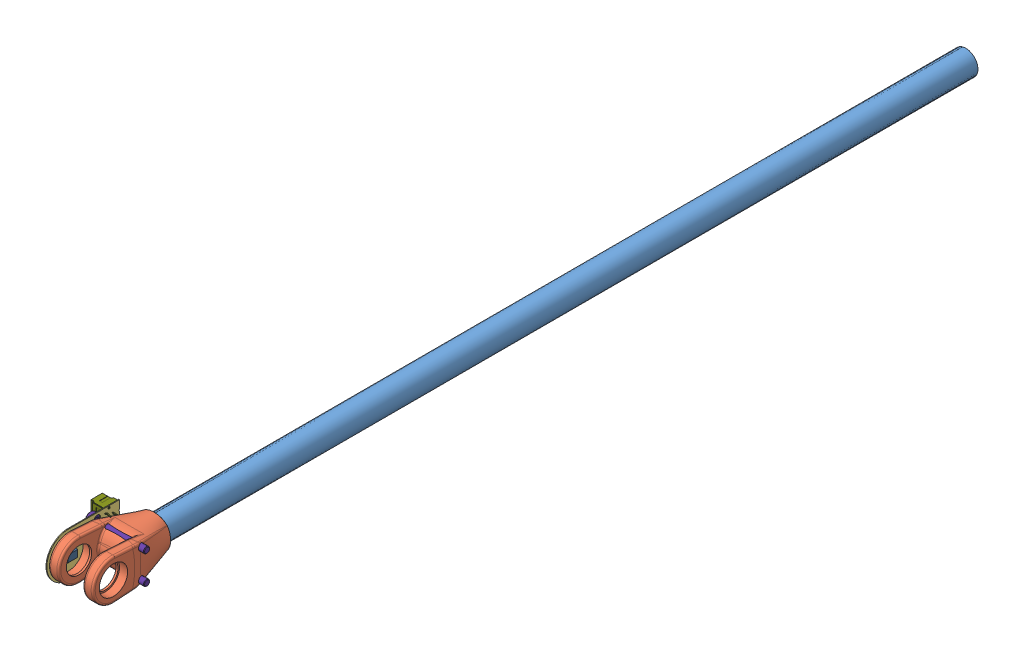
SolidWorks assembly Tilt_Joint, configuration Default. Lengths in mm.
Overall size (31.95 100.9 442.9).
34 component instances, 17 part files, 17 mates.
Components (placement in the parent):
- CF Tube-1: CF Tube [Full Length] x (1 0 0) z (0 -1 0) size (12 420 12)
- Tilt_Joint_Outside-1: Tilt_Joint_Outside [Default] at (0 0 432) x (-1 0 0) z (0 0 -1) size (22.1 20.15 42.34)
- Encoder_Board_REV_A-1: Encoder_Board_REV_A [Default] at (-11 -90 384) x (0 0 1) z (-1 0 0) size (58.9 100.9 10.35)
  - Encoder_Board_REV_A_BOARD-1: Encoder_Board_REV_A_BOARD [Default] at origin size (58.9 100.9 0.41)
  - RESC0603(1608)_N_CMP-009-00178-1-1: RESC0603(1608)_N_CMP-009-00178-1 [Default] at (38.479 98.166 0.4013) size (1.7 0.95 0.6)
  - WL-SMCW_0603_150060xx75000_CMP-007-00036-1-1: WL-SMCW_0603_150060xx75000_CMP-007-00036-1 [Default] at (41.273 97.366 0.4013) x (0 -1 0) z (0 0 1) size (1.6 0.8 0.7)
  - RESC1608X55X25NL10T15_CMP-009-00017-7-1: RESC1608X55X25NL10T15_CMP-009-00017-7 [Default] at (43.17 92.667 0.4013) x (0 1 0) z (0 0 1) size (1.7 0.9 0.55)
  - RESC1608X55X25NL10T15_CMP-009-00017-7-2: RESC1608X55X25NL10T15_CMP-009-00017-7 [Default] at (43.17 90 0.4013) x (0 -1 0) z (0 0 1) size (1.7 0.9 0.55)
  - RESC1608X55X25NL10T15_CMP-009-00017-7-3: RESC1608X55X25NL10T15_CMP-009-00017-7 [Default] at (34.669 90 0.4013) x (0 -1 0) z (0 0 1) size (1.7 0.9 0.55)
  - RESC1608X55X25NL10T15_CMP-009-00017-7-4: RESC1608X55X25NL10T15_CMP-009-00017-7 [Default] at (34.669 92.667 0.4013) x (0 1 0) z (0 0 1) size (1.7 0.9 0.55)
  - RESC1608X55X25NL10T15_CMP-009-00017-7-5: RESC1608X55X25NL10T15_CMP-009-00017-7 [Default] at (41.273 88.349 0.4013) x (0 -1 0) z (0 0 1) size (1.7 0.9 0.55)
  - RESC1608X55X25NL10T15_CMP-009-00017-7-6: RESC1608X55X25NL10T15_CMP-009-00017-7 [Default] at (45.2753 87.3443 0.4013) x (-1 0 0) z (0 0 1) size (1.7 0.9 0.55)
  - ONSC-SOT-23-3-318-08_V_CMP-004-00032-1-1: ONSC-SOT-23-3-318-08_V_CMP-004-00032-1 [Default] at (36.336 84.097 0.4013) x (-1 0 0) z (0 0 1) size (1.3 2.92 1.1)
  - ONSC-SOT-23-3-318-08_V_CMP-004-00032-1-2: ONSC-SOT-23-3-318-08_V_CMP-004-00032-1 [Default] at (33.0374 93.1229 0.2207) x (-1 0 0) z (0 0 1) size (1.3 2.92 1.1)
  - FP-SOT505-1-IPC_C_CMP-015-00010-1-1: FP-SOT505-1-IPC_C_CMP-015-00010-1 [Default] at (39.106 91.397 0.4013) size (4.9 3.03 1.13)
  - CAPC1608X90X40NL10T20_CMP-001-00017-7-1: CAPC1608X90X40NL10T20_CMP-001-00017-7 [Default] at (36.947 94.445 0.4013) x (0 -1 0) z (0 0 1) size (1.7 0.9 0.9)
  - CAPC1608X90X40NL10T20_CMP-001-00017-7-2: CAPC1608X90X40NL10T20_CMP-001-00017-7 [Default] at (41.265 94.445 0.4013) x (0 -1 0) z (0 0 1) size (1.7 0.9 0.9)
  - CAPC1608X90X40NL10T20_CMP-001-00017-7-3: CAPC1608X90X40NL10T20_CMP-001-00017-7 [Default] at (45.923 92.5541 0.4013) x (0 1 0) z (0 0 1) size (1.7 0.9 0.9)
  - AS5600L-ASOM-Footprint-1_CMP-010-00024-5-1: AS5600L-ASOM-Footprint-1_CMP-010-00024-5 [Default] at (48 90 0.0102) x (0 -1 0) z (0 0 -1) size (6 4.91 1.76)
  - FP-S2761-46R-MFG_CMP-002-00072-3-1: FP-S2761-46R-MFG_CMP-002-00072-3 [Default] at (40.003 85.047 0.4013) x (0 1 0) z (0 0 1) size (1.6 0.8 1.28)
  - FP-S2761-46R-MFG_CMP-002-00072-3-2: FP-S2761-46R-MFG_CMP-002-00072-3 [Default] at (48.766 83.142 0.4013) x (0 -1 0) z (0 0 1) size (1.6 0.8 1.28)
  - FP-S2761-46R-MFG_CMP-002-00072-3-3: FP-S2761-46R-MFG_CMP-002-00072-3 [Default] at (44.575 83.142 0.4013) x (0 -1 0) z (0 0 1) size (1.6 0.8 1.28)
  - FP-S2761-46R-MFG_CMP-002-00072-3-4: FP-S2761-46R-MFG_CMP-002-00072-3 [Default] at (47.115 96.604 0.4013) x (-1 0 0) z (0 0 1) size (1.6 0.8 1.28)
  - FP-S2761-46R-MFG_CMP-002-00072-3-5: FP-S2761-46R-MFG_CMP-002-00072-3 [Default] at (53.211 91.651 0.4013) x (0 -1 0) z (0 0 1) size (1.6 0.8 1.28)
  - CAPC1608X90X35NL15T15_CMP-001-00004-7-1: CAPC1608X90X35NL15T15_CMP-001-00004-7 [Default] at (48.131 92.413 0.4013) x (-1 0 0) z (0 0 1) size (1.75 0.95 0.9)
  - RESC1608X55X25NL10T15_CMP-009-00017-7-7: RESC1608X55X25NL10T15_CMP-009-00017-7 [Default] at (49.782 86.825 0.4013) x (0 -1 0) z (0 0 1) size (1.7 0.9 0.55)
  - RESC1608X55X25NL10T15_CMP-009-00006-7-1: RESC1608X55X25NL10T15_CMP-009-00006-7 [Default] at (39.106 88.984 0.4013) size (1.7 0.9 0.55)
  - RESC1608X55X25NL10T15_CMP-009-00006-7-2: RESC1608X55X25NL10T15_CMP-009-00006-7 [Default] at (39.106 93.81 0.4013) size (1.7 0.9 0.55)
  - CAP_CER_10UF_16V_X5R_0805-Footprint-1_CMP-001-00084-3-1: CAP_CER_10UF_16V_X5R_0805-Footprint-1_CMP-001-00084-3 [Default] at (32.8327 89.3036 0.0434) x (-1 0 0) z (0 0 1) size (2 1.25 1.35)
  - FP-SMA-MFG_CMP-004-00031-3-1: FP-SMA-MFG_CMP-004-00031-3 [Default] at (27.9685 90.1092 0.0267) x (-1 0 0) z (0 0 1) size (5.2 2.69 2.44)
  - 5031750400-Footprint-1_CMP-002-00074-2-1: 5031750400-Footprint-1_CMP-002-00074-2 [Default] at (30.1173 98.5457 0.4013) x (-0.008727 -0.999962 0) z (0 0 1) size (8.9 7.25 10.35)
  - 5031750400-Footprint-1_CMP-002-00074-2-2: 5031750400-Footprint-1_CMP-002-00074-2 [Default] at (30.1173 86.2787 0.4013) x (-0.008727 -0.999962 0) z (0 0 1) size (8.9 7.25 10.35)
- socket head cap screw_am-1: socket head cap screw_am [B18.3.1M - 3 x 0.5 x 25 Hex SHCS -- 18NHX] at (-14.4115 7 418) size (28 5.5 5.5)
- socket head cap screw_am-2: socket head cap screw_am [B18.3.1M - 3 x 0.5 x 25 Hex SHCS -- 18NHX] at (-14.4115 -7 418) size (28 5.5 5.5)
Mates (geometry in assembly coordinates):
- Coincident1: coincident anti-aligned: plane of CF Tube-1 through (0 0 420) normal (0 0 1); plane of Tilt_Joint-1 through (0 0 420) normal (0 0 -1)
- Concentric1: concentric aligned: cylinder of CF Tube-1 through (0 0 420) axis (0 0 -1) radius 6; cylinder of Tilt_Joint-1 through (0 0 420) axis (0 0 -1) radius 6
- Coincident2: coincident anti-aligned: plane of CF Tube-1 through (0 0 0) normal (0 -1 0)
- Coincident3: coincident aligned: plane of CF Tube-1 through (0 0 0) normal (1 0 0)
- Coincident4: coincident aligned: plane of CF Tube-1 through (0 0 0) normal (0 0 1)
- Parallel2: parallel aligned: plane of Tilt_Joint-1 through (0 0 432) normal (0 1 0)
- Distance1: distance = 1 mm anti-aligned: plane of RJ11_4P4C-1 through (-12 1.9985 408.4516) normal (1 0 0); plane of Tilt_Joint_Outside-1 through (-11 0 432) normal (-1 0 0)
- Distance2: distance = 1 mm anti-aligned: plane of RJ11_4P4C-3 through (-12 -13.201 408.5843) normal (1 0 0); plane of Tilt_Joint_Outside-1 through (-11 0 432) normal (-1 0 0)
- Distance4: distance = 3 mm anti-aligned: plane of RJ11_4P4C-1 through (-12.5 1.3918 401.9567) normal (0 -0.999962 0.008727); plane of RJ11_4P4C-3 through (-12.5 -1.4947 414.9823) normal (0 0.999962 -0.008727)
- Coincident7: coincident aligned: plane of RJ11_4P4C-1 through (-12.5 6.4741 401.1345) normal (0 -0.008727 -0.999962); plane of RJ11_4P4C-3 through (-12.5 -8.7253 401.2671) normal (0 -0.008727 -0.999962)
- Distance5: distance = 1 mm anti-aligned: plane of RJ9_4P4C-1 through (-12 5.4635 407.2535) normal (1 0 0); plane of Tilt_Joint_Outside-1 through (-11 0 432) normal (-1 0 0)
- Coincident8: coincident anti-aligned: plane of Tilt_Joint_Outside-1 through (-11 0 432) normal (-1 0 0); plane of Encoder_Board_REV_A-1/Encoder_Board_REV_A_BOARD-1 through (-11 0 432) normal (1 0 0)
- Concentric2: concentric aligned: cylinder of Tilt_Joint_Outside-1 through (-11 0 432) axis (1 0 0) radius 10; cylinder of Encoder_Board_REV_A-1/Encoder_Board_REV_A_BOARD-1 through (-11.4115 0 432) axis (1 0 0) radius 10.9
- Concentric3: concentric: cylinder of Encoder_Board_REV_A-1/Encoder_Board_REV_A_BOARD-1 through (-11 7 414) axis (-1 0 0) radius 1.65; cylinder of socket head cap screw_am-1 through (-46.1615 7 414) axis (-1 0 0) radius 2.75
- Coincident9: coincident anti-aligned: plane of Encoder_Board_REV_A-1/Encoder_Board_REV_A_BOARD-1 through (-11.4115 0 432) normal (-1 0 0); plane of socket head cap screw_am-1 through (-11.4115 9.75 418) normal (1 0 0)
- Concentric4: concentric: cylinder of Encoder_Board_REV_A-1/Encoder_Board_REV_A_BOARD-1 through (-11 -7 414) axis (-1 0 0) radius 1.65; cylinder of socket head cap screw_am-2 through (-46.1615 -7 414) axis (-1 0 0) radius 2.75
- Coincident10: coincident anti-aligned: plane of Encoder_Board_REV_A-1/Encoder_Board_REV_A_BOARD-1 through (-11.4115 0 432) normal (-1 0 0); plane of socket head cap screw_am-2 through (-11.4115 -4.25 418) normal (1 0 0)
